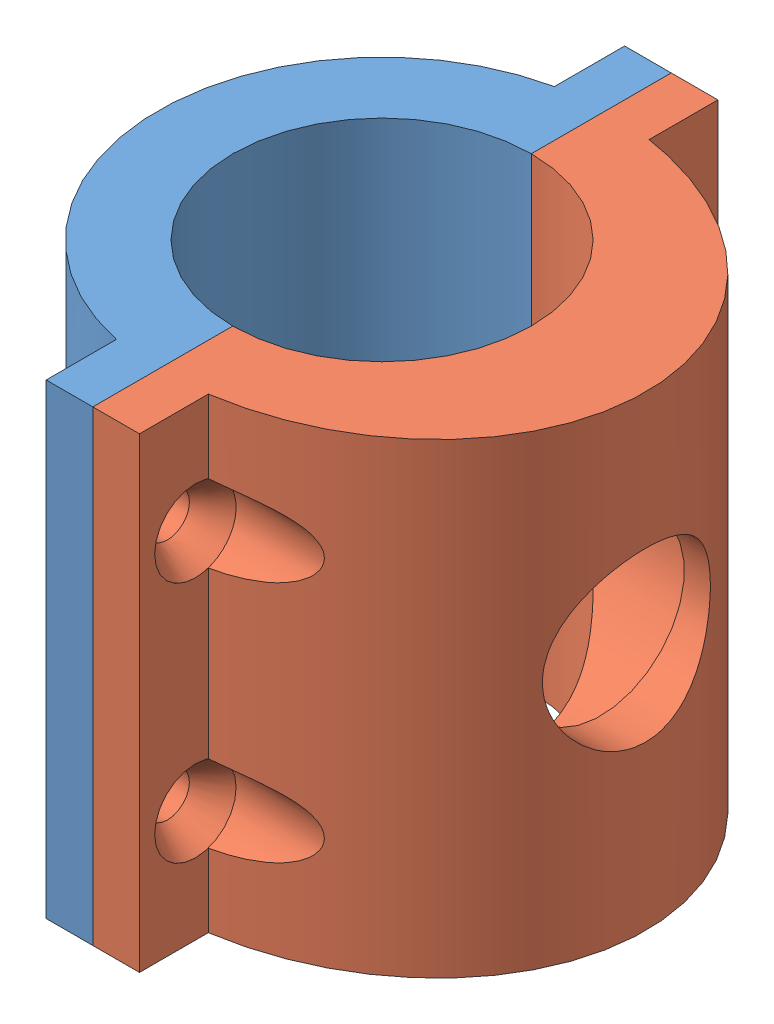
SolidWorks assembly TileHolderV1, configuration Default. Lengths in mm.
Overall size (52.82 50 62).
2 component instances, 2 part files, 4 mates.
Components (placement in the parent):
- tileholderback-1: tileholderback [Default] at (-28.7535 -50 -26.9099) size (24 50 62)
- tileholderfront-1: tileholderfront [Default] at (-28.7535 -50 -26.9099) x (-1 0 0) z (0 0 -1) size (28.82 50 62)
Mates (geometry in assembly coordinates):
- Coincident1: coincident anti-aligned: plane of tile holder back-1 through (-28.7535 0 -10.9099) normal (1 0 0); plane of tileholderfront-1 through (-28.7535 0 -10.9099) normal (-1 0 0)
- Coincident2: coincident aligned: plane of tile holder back-1 through (-28.7535 0 -26.9099) normal (0 1 0); plane of tileholderfront-1 through (-28.7535 0 -26.9099) normal (0 1 0)
- Coincident3: coincident aligned: plane of tile holder back-1 through (-33.7535 0 4.0901) normal (0 0 1); plane of tileholderfront-1 through (-28.7535 0 4.0901) normal (0 0 1)
- Coincident4: coincident aligned: plane of tileholderfront-1 through (-28.7535 0 -26.9099) normal (0 1 0)
